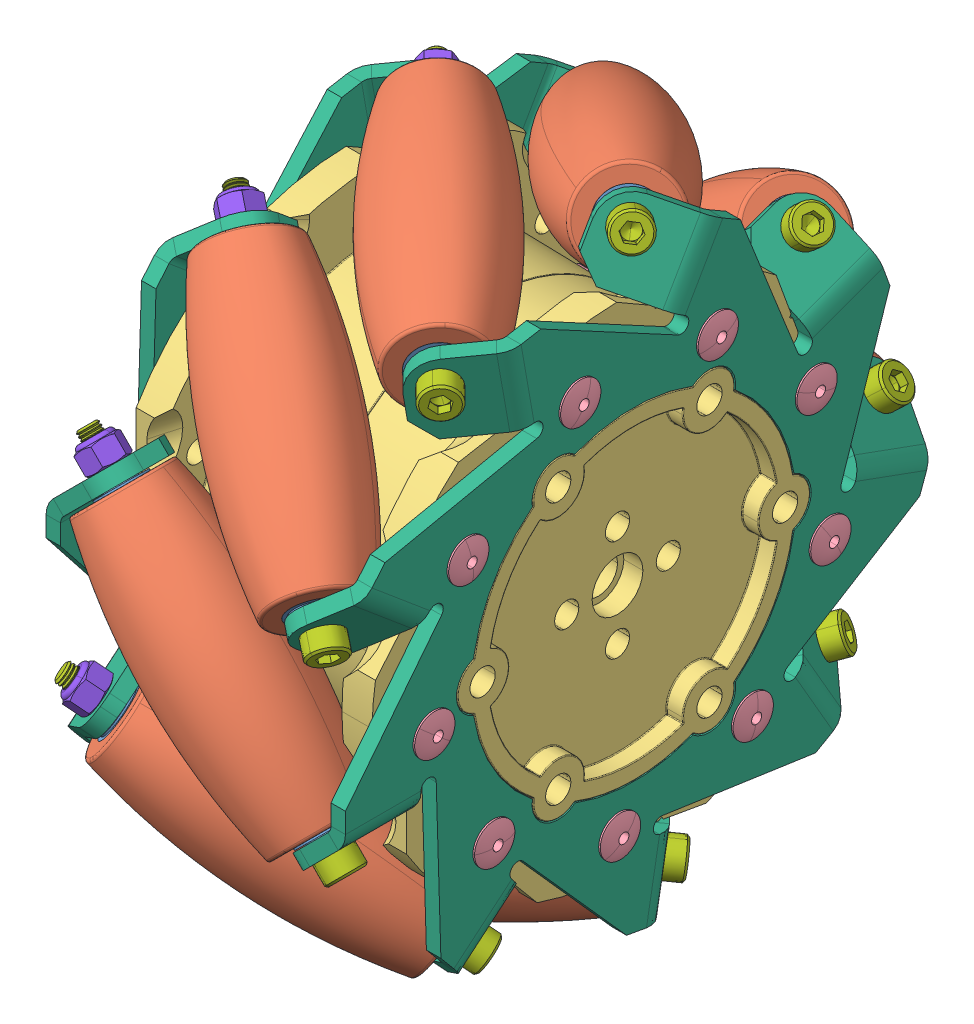
SolidWorks assembly am-3919L 4in HD FTC Mecanum Left.STEP, configuration Default. Lengths in mm.
Overall size (48.73 122.77 122.26).
76 component instances, 8 part files, 0 mates.
Components (placement in the parent):
- 4HD Mecanum Roller V2.STEP-1: 4HD Mecanum Roller V2.STEP [Default] at (-18.8109 20.2849 9.9476) x (0.707107 -0.122788 0.696364) z (0.14334 0.989252 0.028881) size (44.96 19.05 19.05)
  - 4HD Mecanum Roller Core .STEP-1: 4HD Mecanum Roller Core .STEP [Default] at (23.9168 28.1416 25.8115) size (44.96 13.97 13.97)
  - 4HD Mecanum roller skin.STEP-1: 4HD Mecanum roller skin.STEP [Default] at (23.9168 28.1416 25.8115) size (44.45 19.05 19.05)
- 4HD Mecanum Roller V2.STEP-2: 4HD Mecanum Roller V2.STEP [Default] at (-18.8109 9.1449 20.6592) x (0.707107 -0.541675 0.454519) z (0.14334 0.739247 0.658003) size (44.96 19.05 19.05)
  - 4HD Mecanum Roller Core .STEP-1: 4HD Mecanum Roller Core .STEP [Default] at (23.9168 28.1416 25.8115) size (44.96 13.97 13.97)
  - 4HD Mecanum roller skin.STEP-1: 4HD Mecanum roller skin.STEP [Default] at (23.9168 28.1416 25.8115) size (44.45 19.05 19.05)
- 4HD Mecanum Roller V2.STEP-3: 4HD Mecanum Roller V2.STEP [Default] at (-18.8109 -6.2741 21.7041) x (0.707107 -0.707107 0) z (0.14334 0.14334 0.979238) size (44.96 19.05 19.05)
  - 4HD Mecanum Roller Core .STEP-1: 4HD Mecanum Roller Core .STEP [Default] at (23.9168 28.1416 25.8115) size (44.96 13.97 13.97)
  - 4HD Mecanum roller skin.STEP-1: 4HD Mecanum roller skin.STEP [Default] at (23.9168 28.1416 25.8115) size (44.45 19.05 19.05)
- 4HD Mecanum Roller V2.STEP-4: 4HD Mecanum Roller V2.STEP [Default] at (-18.8109 -18.7573 12.5934) x (0.707107 -0.541675 -0.454519) z (0.14334 -0.519637 0.842277) size (44.96 19.05 19.05)
  - 4HD Mecanum Roller Core .STEP-1: 4HD Mecanum Roller Core .STEP [Default] at (23.9168 28.1416 25.8115) size (44.96 13.97 13.97)
  - 4HD Mecanum roller skin.STEP-1: 4HD Mecanum roller skin.STEP [Default] at (23.9168 28.1416 25.8115) size (44.45 19.05 19.05)
- 4HD Mecanum Roller V2.STEP-5: 4HD Mecanum Roller V2.STEP [Default] at (-18.8109 -22.4638 -2.4099) x (0.707107 -0.122788 -0.696364) z (0.14334 -0.939471 0.311205) size (44.96 19.05 19.05)
  - 4HD Mecanum Roller Core .STEP-1: 4HD Mecanum Roller Core .STEP [Default] at (23.9168 28.1416 25.8115) size (44.96 13.97 13.97)
  - 4HD Mecanum roller skin.STEP-1: 4HD Mecanum roller skin.STEP [Default] at (23.9168 28.1416 25.8115) size (44.45 19.05 19.05)
- 4HD Mecanum Roller V2.STEP-6: 4HD Mecanum Roller V2.STEP [Default] at (-18.8109 -15.6593 -16.2856) x (0.707107 0.353553 -0.612372) z (0.14334 -0.919715 -0.365483) size (44.96 19.05 19.05)
  - 4HD Mecanum Roller Core .STEP-1: 4HD Mecanum Roller Core .STEP [Default] at (23.9168 28.1416 25.8115) size (44.96 13.97 13.97)
  - 4HD Mecanum roller skin.STEP-1: 4HD Mecanum roller skin.STEP [Default] at (23.9168 28.1416 25.8115) size (44.45 19.05 19.05)
- 4HD Mecanum Roller V2.STEP-7: 4HD Mecanum Roller V2.STEP [Default] at (-18.8109 -1.5275 -22.541) x (0.707107 0.664463 -0.241845) z (0.14334 -0.469615 -0.871158) size (44.96 19.05 19.05)
  - 4HD Mecanum Roller Core .STEP-1: 4HD Mecanum Roller Core .STEP [Default] at (23.9168 28.1416 25.8115) size (44.96 13.97 13.97)
  - 4HD Mecanum roller skin.STEP-1: 4HD Mecanum roller skin.STEP [Default] at (23.9168 28.1416 25.8115) size (44.45 19.05 19.05)
- 4HD Mecanum Roller V2.STEP-8: 4HD Mecanum Roller V2.STEP [Default] at (-18.8109 13.3189 -18.2493) x (0.707107 0.664463 0.241845) z (0.14334 0.200224 -0.969208) size (44.96 19.05 19.05)
  - 4HD Mecanum Roller Core .STEP-1: 4HD Mecanum Roller Core .STEP [Default] at (23.9168 28.1416 25.8115) size (44.96 13.97 13.97)
  - 4HD Mecanum roller skin.STEP-1: 4HD Mecanum roller skin.STEP [Default] at (23.9168 28.1416 25.8115) size (44.45 19.05 19.05)
- 4HD Mecanum Roller V2.STEP-9: 4HD Mecanum Roller V2.STEP [Default] at (-18.8109 21.9333 -5.4185) x (0.707107 0.353553 0.612372) z (0.14334 0.776375 -0.613755) size (44.96 19.05 19.05)
  - 4HD Mecanum Roller Core .STEP-1: 4HD Mecanum Roller Core .STEP [Default] at (23.9168 28.1416 25.8115) size (44.96 13.97 13.97)
  - 4HD Mecanum roller skin.STEP-1: 4HD Mecanum roller skin.STEP [Default] at (23.9168 28.1416 25.8115) size (44.45 19.05 19.05)
- ip-3xxx_half 4HD FTC Mecanum Hub.STEP-1: ip-3xxx_half 4HD FTC Mecanum Hub.STEP [Default] at origin size (25.6 79.24 78.04)
- ip-3xxx_half 4HD FTC Mecanum Hub.STEP-2: ip-3xxx_half 4HD FTC Mecanum Hub.STEP [Default] at (42.5704 0 0) x (-1 0 0) z (0 0 1) size (25.6 79.24 78.04)
- 125 rivet.STEP-1: 125 rivet.STEP [Default] at (36.1252 -22.7384 22.1591) x (0 -1 0) z (0 0 1) size (6.35 9.53 6.35)
- Brass tube.STEP-1: Brass tube.STEP [Default] at (5.3017 43.4237 -8.5747) x (0.707107 -0.122788 0.696364) z (-0.167214 0.927839 0.333397) size (45.21 4.76 4.76)
- ip-3026L_plate 4 HD Left Mecanum Plate_DefaultSM-FLAT-PATTERN.STEP-1: ip-3026L_plate 4 HD Left Mecanum Plate_DefaultSM-FLAT-PATTERN.STEP [Default] at (42.5704 -40.6479 7.1673) x (1 0 0) z (0 -0.173648 -0.984808) size (10.6 95.17 96.01)
- ip-3026L_plate 4 HD Left Mecanum Plate_DefaultSM-FLAT-PATTERN.STEP-2: ip-3026L_plate 4 HD Left Mecanum Plate_DefaultSM-FLAT-PATTERN.STEP [Default] at (0 -14.1169 -38.7858) x (-1 0 0) z (0 -0.939693 0.34202) size (10.6 95.17 96.01)
- 125 rivet.STEP-2: 125 rivet.STEP [Default] at (6.4452 22.7384 22.1591) x (0 -0.381849 0.924225) z (0 -0.924225 -0.381849) size (6.35 9.53 6.35)
- 125 rivet.STEP-3: 125 rivet.STEP [Default] at (6.4452 3.175 31.5909) x (0 -0.886594 0.462549) z (0 -0.462549 -0.886594) size (6.35 9.53 6.35)
- 125 rivet.STEP-4: 125 rivet.STEP [Default] at (6.4452 -17.874 26.2408) x (0 -0.976491 -0.215558) z (0 0.215558 -0.976491) size (6.35 9.53 6.35)
- 125 rivet.STEP-5: 125 rivet.STEP [Default] at (6.4452 -30.5596 8.6125) x (0 -0.609477 -0.792804) z (0 0.792804 -0.609477) size (6.35 9.53 6.35)
- 125 rivet.STEP-6: 125 rivet.STEP [Default] at (6.4452 -28.946 -13.0458) x (0 0.042718 -0.999087) z (0 0.999087 0.042718) size (6.35 9.53 6.35)
- 125 rivet.STEP-7: 125 rivet.STEP [Default] at (6.4452 -13.7882 -28.5998) x (0 0.674924 -0.737887) z (0 0.737887 0.674924) size (6.35 9.53 6.35)
- 125 rivet.STEP-8: 125 rivet.STEP [Default] at (6.4452 7.8212 -30.7716) x (0 0.991327 -0.131421) z (0 0.131421 0.991327) size (6.35 9.53 6.35)
- 125 rivet.STEP-9: 125 rivet.STEP [Default] at (6.4452 25.771 -18.5451) x (0 0.843876 0.536538) z (0 -0.536538 0.843876) size (6.35 9.53 6.35)
- 125 rivet.STEP-10: 125 rivet.STEP [Default] at (6.4452 31.6622 2.3589) x (0 0.301567 0.953445) z (0 -0.953445 0.301567) size (6.35 9.53 6.35)
- Brass tube.STEP-2: Brass tube.STEP [Default] at (5.3017 38.7762 21.3436) x (0.707107 -0.541675 0.454519) z (-0.167214 0.496463 0.851801) size (45.21 4.76 4.76)
- Brass tube.STEP-3: Brass tube.STEP [Default] at (5.3017 15.9849 41.275) x (0.707107 -0.707107 0) z (-0.167214 -0.167214 0.971637) size (45.21 4.76 4.76)
- Brass tube.STEP-4: Brass tube.STEP [Default] at (5.3017 -14.2859 41.8934) x (0.707107 -0.541675 -0.454519) z (-0.167214 -0.75265 0.636834) size (45.21 4.76 4.76)
- Brass tube.STEP-5: Brass tube.STEP [Default] at (5.3017 -37.8722 22.9093) x (0.707107 -0.122788 -0.696364) z (-0.167214 -0.985912 0.004049) size (45.21 4.76 4.76)
- Brass tube.STEP-6: Brass tube.STEP [Default] at (5.3017 -43.7376 -6.7942) x (0.707107 0.353553 -0.612372) z (-0.167214 -0.757855 -0.63063) size (45.21 4.76 4.76)
- Brass tube.STEP-7: Brass tube.STEP [Default] at (5.3017 -29.1377 -33.3187) x (0.707107 0.664463 -0.241845) z (-0.167214 -0.175189 -0.970231) size (45.21 4.76 4.76)
- Brass tube.STEP-8: Brass tube.STEP [Default] at (5.3017 -0.904 -44.253) x (0.707107 0.664463 0.241845) z (-0.167214 0.489449 -0.85585) size (45.21 4.76 4.76)
- Brass tube.STEP-9: Brass tube.STEP [Default] at (5.3017 27.7528 -34.4808) x (0.707107 0.353553 0.612372) z (-0.167214 0.92507 -0.341007) size (45.21 4.76 4.76)
- 125 rivet.STEP-11: 125 rivet.STEP [Default] at (36.1252 -31.6622 2.3589) x (0 -0.766044 -0.642788) z (0 -0.642788 0.766044) size (6.35 9.53 6.35)
- 125 rivet.STEP-12: 125 rivet.STEP [Default] at (36.1252 -25.771 -18.5451) x (0 -0.173648 -0.984808) z (0 -0.984808 0.173648) size (6.35 9.53 6.35)
- 125 rivet.STEP-13: 125 rivet.STEP [Default] at (36.1252 -7.8212 -30.7716) x (0 0.5 -0.866025) z (0 -0.866025 -0.5) size (6.35 9.53 6.35)
- 125 rivet.STEP-14: 125 rivet.STEP [Default] at (36.1252 13.7882 -28.5998) x (0 0.939693 -0.34202) z (0 -0.34202 -0.939693) size (6.35 9.53 6.35)
- 125 rivet.STEP-15: 125 rivet.STEP [Default] at (36.1252 28.946 -13.0458) x (0 0.939693 0.34202) z (0 0.34202 -0.939693) size (6.35 9.53 6.35)
- 125 rivet.STEP-16: 125 rivet.STEP [Default] at (36.1252 30.5596 8.6125) x (0 0.5 0.866025) z (0 0.866025 -0.5) size (6.35 9.53 6.35)
- 125 rivet.STEP-17: 125 rivet.STEP [Default] at (36.1252 17.874 26.2408) x (0 -0.173648 0.984808) z (0 0.984808 0.173648) size (6.35 9.53 6.35)
- 125 rivet.STEP-18: 125 rivet.STEP [Default] at (36.1252 -3.175 31.5909) x (0 -0.766044 0.642788) z (0 0.642788 0.766044) size (6.35 9.53 6.35)
- SHCS M3 x 55mm_B18.3.1M - 3 x 0.5 x 55 Hex SHCS -- 18SHX.STEP-1: SHCS M3 x 55mm_B18.3.1M - 3 x 0.5 x 55 Hex SHCS -- 18SHX.STEP [Default] at (41.0064 37.2231 26.5903) x (-0.707107 0.122788 -0.696364) z (-0.141632 0.940257 0.309609) size (58 5.5 5.5)
- M3 x 0.5 Nylock Nut.STEP-1: M3 x 0.5 Nylock Nut.STEP [Default] at (3.6839 43.7041 -10.1652) x (-0.696877 0.045899 0.715721) z (-0.707107 0.122788 -0.696364) size (6.23 6.22 3.81)
- M3 x 0.5 Nylock Nut.STEP-2: M3 x 0.5 Nylock Nut.STEP [Default] at (3.6839 40.0134 20.3055) x (-0.696877 -0.424895 0.577777) z (-0.707107 0.541675 -0.454519) size (6.23 6.22 3.81)
- M3 x 0.5 Nylock Nut.STEP-3: M3 x 0.5 Nylock Nut.STEP [Default] at (3.6839 17.5999 41.275) x (-0.696877 -0.696877 0.169485) z (-0.707107 0.707107 0) size (6.23 6.22 3.81)
- M3 x 0.5 Nylock Nut.STEP-4: M3 x 0.5 Nylock Nut.STEP [Default] at (3.6839 -13.0487 42.9315) x (-0.696877 -0.642782 -0.31811) z (-0.707107 0.541675 0.454519) size (6.23 6.22 3.81)
- M3 x 0.5 Nylock Nut.STEP-5: M3 x 0.5 Nylock Nut.STEP [Default] at (3.6839 -37.5917 24.4999) x (-0.696877 -0.287922 -0.656859) z (-0.707107 0.122788 0.696364) size (6.23 6.22 3.81)
- M3 x 0.5 Nylock Nut.STEP-6: M3 x 0.5 Nylock Nut.STEP [Default] at (3.6839 -44.5452 -5.3955) x (-0.696877 0.20166 -0.688256) z (-0.707107 -0.353553 0.612372) size (6.23 6.22 3.81)
- M3 x 0.5 Nylock Nut.STEP-7: M3 x 0.5 Nylock Nut.STEP [Default] at (3.6839 -30.6554 -32.7663) x (-0.696877 0.596883 -0.39761) z (-0.707107 -0.664463 0.241845) size (6.23 6.22 3.81)
- M3 x 0.5 Nylock Nut.STEP-8: M3 x 0.5 Nylock Nut.STEP [Default] at (3.6839 -2.4216 -44.8053) x (-0.696877 0.712817 0.079082) z (-0.707107 -0.664463 -0.241845) size (6.23 6.22 3.81)
- M3 x 0.5 Nylock Nut.STEP-9: M3 x 0.5 Nylock Nut.STEP [Default] at (3.6839 26.9452 -35.8795) x (-0.696877 0.495217 0.51877) z (-0.707107 -0.353553 -0.612372) size (6.23 6.22 3.81)
- SHCS M3 x 55mm_B18.3.1M - 3 x 0.5 x 55 Hex SHCS -- 18SHX.STEP-2: SHCS M3 x 55mm_B18.3.1M - 3 x 0.5 x 55 Hex SHCS -- 18SHX.STEP [Default] at (41.0064 11.4227 44.2959) x (-0.707107 0.541675 -0.454519) z (-0.141632 0.521266 0.84156) size (58 5.5 5.5)
- SHCS M3 x 55mm_B18.3.1M - 3 x 0.5 x 55 Hex SHCS -- 18SHX.STEP-3: SHCS M3 x 55mm_B18.3.1M - 3 x 0.5 x 55 Hex SHCS -- 18SHX.STEP [Default] at (41.0064 -19.7226 41.275) x (-0.707107 0.707107 0) z (-0.141632 -0.141632 0.979735) size (58 5.5 5.5)
- SHCS M3 x 55mm_B18.3.1M - 3 x 0.5 x 55 Hex SHCS -- 18SHX.STEP-4: SHCS M3 x 55mm_B18.3.1M - 3 x 0.5 x 55 Hex SHCS -- 18SHX.STEP [Default] at (41.0064 -41.6395 18.941) x (-0.707107 0.541675 0.454519) z (-0.141632 -0.738258 0.659482) size (58 5.5 5.5)
- SHCS M3 x 55mm_B18.3.1M - 3 x 0.5 x 55 Hex SHCS -- 18SHX.STEP-5: SHCS M3 x 55mm_B18.3.1M - 3 x 0.5 x 55 Hex SHCS -- 18SHX.STEP [Default] at (41.0064 -44.0727 -12.2557) x (-0.707107 0.122788 0.696364) z (-0.141632 -0.989445 0.030649) size (58 5.5 5.5)
- SHCS M3 x 55mm_B18.3.1M - 3 x 0.5 x 55 Hex SHCS -- 18SHX.STEP-6: SHCS M3 x 55mm_B18.3.1M - 3 x 0.5 x 55 Hex SHCS -- 18SHX.STEP [Default] at (41.0064 -25.8839 -37.7178) x (-0.707107 -0.353553 0.612372) z (-0.141632 -0.77766 -0.612524) size (58 5.5 5.5)
- SHCS M3 x 55mm_B18.3.1M - 3 x 0.5 x 55 Hex SHCS -- 18SHX.STEP-7: SHCS M3 x 55mm_B18.3.1M - 3 x 0.5 x 55 Hex SHCS -- 18SHX.STEP [Default] at (41.0064 4.4163 -45.5313) x (-0.707107 -0.664463 0.241845) z (-0.141632 -0.201999 -0.969091) size (58 5.5 5.5)
- SHCS M3 x 55mm_B18.3.1M - 3 x 0.5 x 55 Hex SHCS -- 18SHX.STEP-8: SHCS M3 x 55mm_B18.3.1M - 3 x 0.5 x 55 Hex SHCS -- 18SHX.STEP [Default] at (41.0064 32.6501 -32.0403) x (-0.707107 -0.664463 -0.241845) z (-0.141632 0.468179 -0.872209) size (58 5.5 5.5)
- SHCS M3 x 55mm_B18.3.1M - 3 x 0.5 x 55 Hex SHCS -- 18SHX.STEP-9: SHCS M3 x 55mm_B18.3.1M - 3 x 0.5 x 55 Hex SHCS -- 18SHX.STEP [Default] at (41.0064 45.6065 -3.5572) x (-0.707107 -0.353553 -0.612372) z (-0.141632 0.919291 -0.367211) size (58 5.5 5.5)
